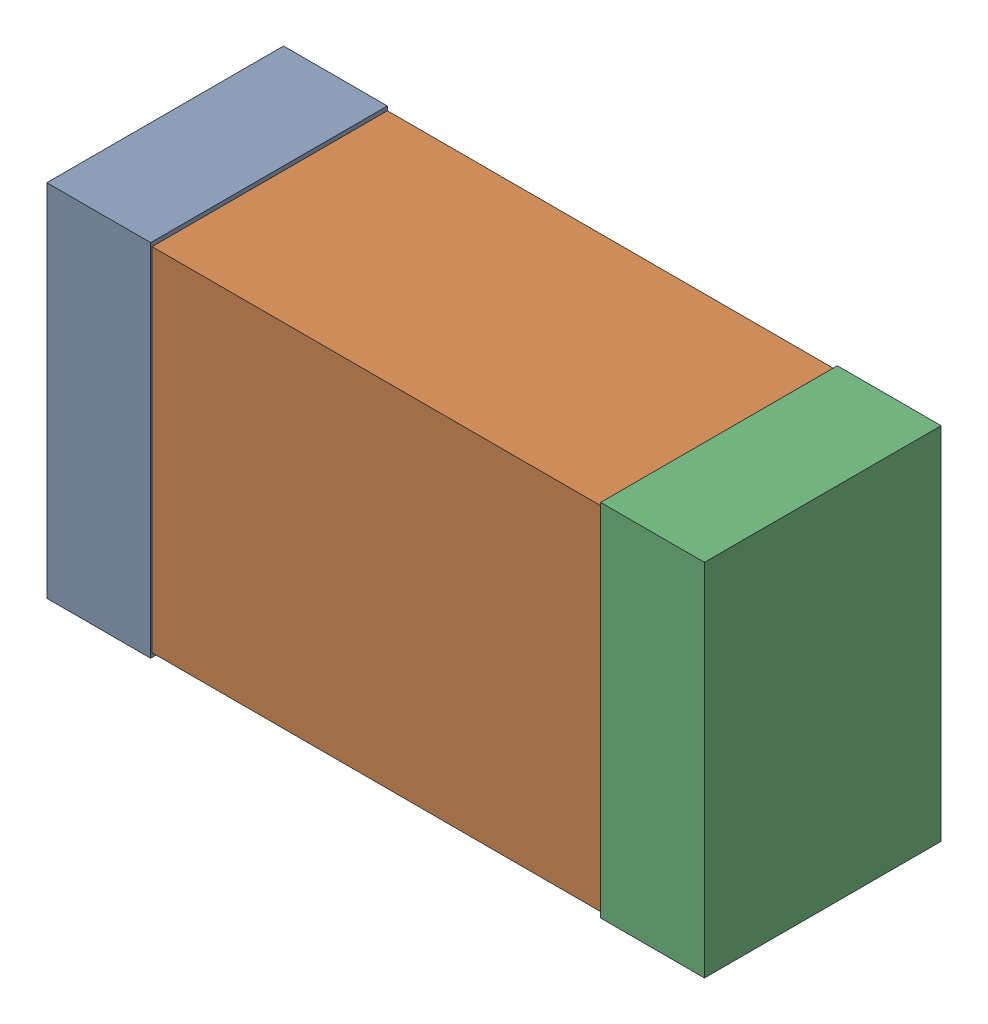
SolidWorks assembly C14_Motor_7Kanaloa_v2.0.0_Motor, configuration Default. Lengths in mm.
Overall size (2.38 1.3 0.85).
6 component instances, 2 part files, 0 mates.
Components (placement in the parent):
- 352877648-1: 352877648 [Default] at (76.676 138.43 0) size (0.38 1.3 0.85)
  - Extruded_14-1: Extruded_14 [Default] at origin size (0.38 1.3 0.85)
- 352877392-1: 352877392 [Default] at (77.676 138.43 0) size (2.2 1.27 0.85)
  - Extruded_15-1: Extruded_15 [Default] at origin size (2.2 1.27 0.85)
- 352877648-2: 352877648 [Default] at (78.676 138.43 0) size (0.38 1.3 0.85)
  - Extruded_14-1: Extruded_14 [Default] at origin size (0.38 1.3 0.85)
